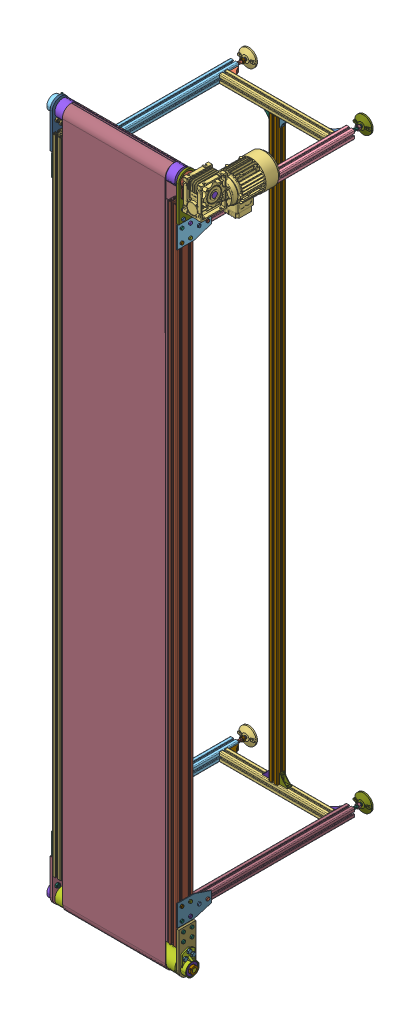
SolidWorks assembly Belt Conveyor.step, configuration Domyślna. Lengths in mm.
Overall size (783.77 3281.47 920.11).
223 component instances, 189 part files, 0 mates.
Components (placement in the parent):
- 8260K11_Mounted Bearing with Three-Bolt Flange.step-1: 8260K11_Mounted Bearing with Three-Bolt Flange.step [Domyślna] at (341.4816 -2455.8636 499.638) x (0 0.005965 0.999982) z (1 0 0) size (100.43 3260.49 665.09)
  - 8260K11_Mounted Bearing with Three-Bolt Flange(Mirror) (3).step-1: 8260K11_Mounted Bearing with Three-Bolt Flange(Mirror) (3).step [Domyślna] at (0 0 -596.825) size (80.98 205.46 51.19)
    - Nut(Mirror) (1).step-1: Nut(Mirror) (1).step [Domyślna] at (0 -65.0875 12.4125) x (-1 0 0) z (0 0 1) size (19.64 19.63 31.4)
    - Nut(Mirror) (1).step-2: Nut(Mirror) (1).step [Domyślna] at (-19 -43.0875 12.4125) x (-1 0 0) z (0 0 1) size (19.64 19.63 31.4)
    - Nut(Mirror) (1).step-3: Nut(Mirror) (1).step [Domyślna] at (19 -43.0875 12.4125) x (-1 0 0) z (0 0 1) size (19.64 19.63 31.4)
    - 4 Hex(Mirror).step-1: 4 Hex(Mirror).step [Domyślna] at (20.8958 -150.1006 3.7625) x (0 0 1) z (-1 0 0) size (21.31 55.25 53.25)
    - 8260K11_Mounted Bearing with Three-Bolt Flange(Mirror) (3)-0.step-1: 8260K11_Mounted Bearing with Three-Bolt Flange(Mirror) (3)-0.step [Domyślna] at origin size (60.74 60.74 12.3)
    - 8260K11_Mounted Bearing with Three-Bolt Flange(Mirror) (3)-1.step-1: 8260K11_Mounted Bearing with Three-Bolt Flange(Mirror) (3)-1.step [Domyślna] at origin size (53.56 53.56 0.76)
    - 8260K11_Mounted Bearing with Three-Bolt Flange(Mirror) (3)-2.step-1: 8260K11_Mounted Bearing with Three-Bolt Flange(Mirror) (3)-2.step [Domyślna] at origin size (50.9 50.9 0.76)
    - 8260K11_Mounted Bearing with Three-Bolt Flange(Mirror) (3)-3.step-1: 8260K11_Mounted Bearing with Three-Bolt Flange(Mirror) (3)-3.step [Domyślna] at origin size (12.3 12.3 12.3)
    - 8260K11_Mounted Bearing with Three-Bolt Flange(Mirror) (3)-4.step-1: 8260K11_Mounted Bearing with Three-Bolt Flange(Mirror) (3)-4.step [Domyślna] at origin size (12.3 12.3 12.3)
    - 8260K11_Mounted Bearing with Three-Bolt Flange(Mirror) (3)-5.step-1: 8260K11_Mounted Bearing with Three-Bolt Flange(Mirror) (3)-5.step [Domyślna] at origin size (12.3 12.3 12.3)
    - 8260K11_Mounted Bearing with Three-Bolt Flange(Mirror) (3)-6.step-1: 8260K11_Mounted Bearing with Three-Bolt Flange(Mirror) (3)-6.step [Domyślna] at origin size (12.3 12.3 12.3)
    - 8260K11_Mounted Bearing with Three-Bolt Flange(Mirror) (3)-7.step-1: 8260K11_Mounted Bearing with Three-Bolt Flange(Mirror) (3)-7.step [Domyślna] at origin size (12.3 12.3 12.3)
    - 8260K11_Mounted Bearing with Three-Bolt Flange(Mirror) (3)-8.step-1: 8260K11_Mounted Bearing with Three-Bolt Flange(Mirror) (3)-8.step [Domyślna] at origin size (12.3 12.3 12.3)
    - 8260K11_Mounted Bearing with Three-Bolt Flange(Mirror) (3)-9.step-1: 8260K11_Mounted Bearing with Three-Bolt Flange(Mirror) (3)-9.step [Domyślna] at origin size (66.58 109.49 25.4)
    - 8260K11_Mounted Bearing with Three-Bolt Flange(Mirror) (3)-10.step-1: 8260K11_Mounted Bearing with Three-Bolt Flange(Mirror) (3)-10.step [Domyślna] at origin size (13.07 13.07 9.52)
    - 8260K11_Mounted Bearing with Three-Bolt Flange(Mirror) (3)-11.step-1: 8260K11_Mounted Bearing with Three-Bolt Flange(Mirror) (3)-11.step [Domyślna] at origin size (33.87 33.87 32.54)
    - 8260K11_Mounted Bearing with Three-Bolt Flange(Mirror) (3)-12.step-1: 8260K11_Mounted Bearing with Three-Bolt Flange(Mirror) (3)-12.step [Domyślna] at origin size (6.25 7.12 6.25)
    - 8260K11_Mounted Bearing with Three-Bolt Flange(Mirror) (3)-13.step-1: 8260K11_Mounted Bearing with Three-Bolt Flange(Mirror) (3)-13.step [Domyślna] at origin size (8.65 8.34 6.25)
    - 8260K11_Mounted Bearing with Three-Bolt Flange(Mirror) (3)-14.step-1: 8260K11_Mounted Bearing with Three-Bolt Flange(Mirror) (3)-14.step [Domyślna] at origin size (80.98 205.46 10)
  - 8260K11_Mounted Bearing with Three-Bolt Flange(Mirror) (4).step-1: 8260K11_Mounted Bearing with Three-Bolt Flange(Mirror) (4).step [Domyślna] at (18.9701 -3180.0156 0) x (0.999929 0.01193 0) z (0 0 -1) size (80.98 205.46 51.19)
    - Nut(Mirror) (2).step-1: Nut(Mirror) (2).step [Domyślna] at (0 -65.0875 12.4125) x (-1 0 0) z (0 0 1) size (19.64 19.63 31.4)
    - Nut(Mirror) (2).step-2: Nut(Mirror) (2).step [Domyślna] at (-19 -43.0875 12.4125) x (-1 0 0) z (0 0 1) size (19.64 19.63 31.4)
    - Nut(Mirror) (2).step-3: Nut(Mirror) (2).step [Domyślna] at (19 -43.0875 12.4125) x (-1 0 0) z (0 0 1) size (19.64 19.63 31.4)
    - 4 Hex(Mirror) (1).step-1: 4 Hex(Mirror) (1).step [Domyślna] at (20.8958 -150.1006 3.7625) x (0 0 1) z (-1 0 0) size (21.31 55.25 53.25)
    - 8260K11_Mounted Bearing with Three-Bolt Flange(Mirror) (4)-15.step-1: 8260K11_Mounted Bearing with Three-Bolt Flange(Mirror) (4)-15.step [Domyślna] at origin size (60.74 60.74 12.3)
    - 8260K11_Mounted Bearing with Three-Bolt Flange(Mirror) (4)-16.step-1: 8260K11_Mounted Bearing with Three-Bolt Flange(Mirror) (4)-16.step [Domyślna] at origin size (53.56 53.56 0.76)
    - 8260K11_Mounted Bearing with Three-Bolt Flange(Mirror) (4)-17.step-1: 8260K11_Mounted Bearing with Three-Bolt Flange(Mirror) (4)-17.step [Domyślna] at origin size (50.9 50.9 0.76)
    - 8260K11_Mounted Bearing with Three-Bolt Flange(Mirror) (4)-18.step-1: 8260K11_Mounted Bearing with Three-Bolt Flange(Mirror) (4)-18.step [Domyślna] at origin size (12.3 12.3 12.3)
    - 8260K11_Mounted Bearing with Three-Bolt Flange(Mirror) (4)-19.step-1: 8260K11_Mounted Bearing with Three-Bolt Flange(Mirror) (4)-19.step [Domyślna] at origin size (12.3 12.3 12.3)
    - 8260K11_Mounted Bearing with Three-Bolt Flange(Mirror) (4)-20.step-1: 8260K11_Mounted Bearing with Three-Bolt Flange(Mirror) (4)-20.step [Domyślna] at origin size (12.3 12.3 12.3)
    - 8260K11_Mounted Bearing with Three-Bolt Flange(Mirror) (4)-21.step-1: 8260K11_Mounted Bearing with Three-Bolt Flange(Mirror) (4)-21.step [Domyślna] at origin size (12.3 12.3 12.3)
    - 8260K11_Mounted Bearing with Three-Bolt Flange(Mirror) (4)-22.step-1: 8260K11_Mounted Bearing with Three-Bolt Flange(Mirror) (4)-22.step [Domyślna] at origin size (12.3 12.3 12.3)
    - 8260K11_Mounted Bearing with Three-Bolt Flange(Mirror) (4)-23.step-1: 8260K11_Mounted Bearing with Three-Bolt Flange(Mirror) (4)-23.step [Domyślna] at origin size (12.3 12.3 12.3)
    - 8260K11_Mounted Bearing with Three-Bolt Flange(Mirror) (4)-24.step-1: 8260K11_Mounted Bearing with Three-Bolt Flange(Mirror) (4)-24.step [Domyślna] at origin size (66.58 109.49 25.4)
    - 8260K11_Mounted Bearing with Three-Bolt Flange(Mirror) (4)-25.step-1: 8260K11_Mounted Bearing with Three-Bolt Flange(Mirror) (4)-25.step [Domyślna] at origin size (13.07 13.07 9.52)
    - 8260K11_Mounted Bearing with Three-Bolt Flange(Mirror) (4)-26.step-1: 8260K11_Mounted Bearing with Three-Bolt Flange(Mirror) (4)-26.step [Domyślna] at origin size (33.87 33.87 32.54)
    - 8260K11_Mounted Bearing with Three-Bolt Flange(Mirror) (4)-27.step-1: 8260K11_Mounted Bearing with Three-Bolt Flange(Mirror) (4)-27.step [Domyślna] at origin size (6.25 7.12 6.25)
    - 8260K11_Mounted Bearing with Three-Bolt Flange(Mirror) (4)-28.step-1: 8260K11_Mounted Bearing with Three-Bolt Flange(Mirror) (4)-28.step [Domyślna] at origin size (8.65 8.34 6.25)
    - 8260K11_Mounted Bearing with Three-Bolt Flange(Mirror) (4)-29.step-1: 8260K11_Mounted Bearing with Three-Bolt Flange(Mirror) (4)-29.step [Domyślna] at origin size (80.98 205.46 10)
  - 8260K11_Mounted Bearing with Three-Bolt Flange(Mirror) (5).step-1: 8260K11_Mounted Bearing with Three-Bolt Flange(Mirror) (5).step [Domyślna] at (0 0 -596.825) size (100.43 3260.49 665.09)
    - 8260K11_Mounted Bearing with Three-Bolt Flange(Mirror) (3)(Mirror) (1).step-1: 8260K11_Mounted Bearing with Three-Bolt Flange(Mirror) (3)(Mirror) (1).step [Domyślna] at (0 0 596.825) size (80.98 205.46 51.19)
      - Nut(Mirror) (1)(Mirror) (1).step-1: Nut(Mirror) (1)(Mirror) (1).step [Domyślna] at (0 -65.0875 -12.4125) x (-1 0 0) z (0 0 1) size (19.64 19.63 31.4)
      - Nut(Mirror) (1)(Mirror) (1).step-2: Nut(Mirror) (1)(Mirror) (1).step [Domyślna] at (-19 -43.0875 -12.4125) x (-1 0 0) z (0 0 1) size (19.64 19.63 31.4)
      - Nut(Mirror) (1)(Mirror) (1).step-3: Nut(Mirror) (1)(Mirror) (1).step [Domyślna] at (19 -43.0875 -12.4125) x (-1 0 0) z (0 0 1) size (19.64 19.63 31.4)
      - 4 Hex(Mirror)(Mirror) (1).step-1: 4 Hex(Mirror)(Mirror) (1).step [Domyślna] at (20.8958 -150.1006 -3.7625) x (0 0 -1) z (1 0 0) size (21.31 55.25 55.26)
      - 8260K11_Mounted Bearing with Three-Bolt Flange(Mirror) (3)(Mirror) (1)-30.step-1: 8260K11_Mounted Bearing with Three-Bolt Flange(Mirror) (3)(Mirror) (1)-30.step [Domyślna] at origin size (60.74 60.74 12.3)
      - 8260K11_Mounted Bearing with Three-Bolt Flange(Mirror) (3)(Mirror) (1)-31.step-1: 8260K11_Mounted Bearing with Three-Bolt Flange(Mirror) (3)(Mirror) (1)-31.step [Domyślna] at origin size (53.56 53.56 0.76)
      - 8260K11_Mounted Bearing with Three-Bolt Flange(Mirror) (3)(Mirror) (1)-32.step-1: 8260K11_Mounted Bearing with Three-Bolt Flange(Mirror) (3)(Mirror) (1)-32.step [Domyślna] at origin size (50.9 50.9 0.76)
      - 8260K11_Mounted Bearing with Three-Bolt Flange(Mirror) (3)(Mirror) (1)-33.step-1: 8260K11_Mounted Bearing with Three-Bolt Flange(Mirror) (3)(Mirror) (1)-33.step [Domyślna] at origin size (12.3 12.3 12.3)
      - 8260K11_Mounted Bearing with Three-Bolt Flange(Mirror) (3)(Mirror) (1)-34.step-1: 8260K11_Mounted Bearing with Three-Bolt Flange(Mirror) (3)(Mirror) (1)-34.step [Domyślna] at origin size (12.3 12.3 12.3)
      - 8260K11_Mounted Bearing with Three-Bolt Flange(Mirror) (3)(Mirror) (1)-35.step-1: 8260K11_Mounted Bearing with Three-Bolt Flange(Mirror) (3)(Mirror) (1)-35.step [Domyślna] at origin size (12.3 12.3 12.3)
      - 8260K11_Mounted Bearing with Three-Bolt Flange(Mirror) (3)(Mirror) (1)-36.step-1: 8260K11_Mounted Bearing with Three-Bolt Flange(Mirror) (3)(Mirror) (1)-36.step [Domyślna] at origin size (12.3 12.3 12.3)
      - 8260K11_Mounted Bearing with Three-Bolt Flange(Mirror) (3)(Mirror) (1)-37.step-1: 8260K11_Mounted Bearing with Three-Bolt Flange(Mirror) (3)(Mirror) (1)-37.step [Domyślna] at origin size (12.3 12.3 12.3)
      - 8260K11_Mounted Bearing with Three-Bolt Flange(Mirror) (3)(Mirror) (1)-38.step-1: 8260K11_Mounted Bearing with Three-Bolt Flange(Mirror) (3)(Mirror) (1)-38.step [Domyślna] at origin size (12.3 12.3 12.3)
      - 8260K11_Mounted Bearing with Three-Bolt Flange(Mirror) (3)(Mirror) (1)-39.step-1: 8260K11_Mounted Bearing with Three-Bolt Flange(Mirror) (3)(Mirror) (1)-39.step [Domyślna] at origin size (66.58 109.49 25.4)
      - 8260K11_Mounted Bearing with Three-Bolt Flange(Mirror) (3)(Mirror) (1)-40.step-1: 8260K11_Mounted Bearing with Three-Bolt Flange(Mirror) (3)(Mirror) (1)-40.step [Domyślna] at origin size (13.07 13.07 9.52)
      - 8260K11_Mounted Bearing with Three-Bolt Flange(Mirror) (3)(Mirror) (1)-41.step-1: 8260K11_Mounted Bearing with Three-Bolt Flange(Mirror) (3)(Mirror) (1)-41.step [Domyślna] at origin size (33.87 33.87 32.54)
      - 8260K11_Mounted Bearing with Three-Bolt Flange(Mirror) (3)(Mirror) (1)-42.step-1: 8260K11_Mounted Bearing with Three-Bolt Flange(Mirror) (3)(Mirror) (1)-42.step [Domyślna] at origin size (6.25 7.12 6.25)
      - 8260K11_Mounted Bearing with Three-Bolt Flange(Mirror) (3)(Mirror) (1)-43.step-1: 8260K11_Mounted Bearing with Three-Bolt Flange(Mirror) (3)(Mirror) (1)-43.step [Domyślna] at origin size (8.65 8.34 6.25)
      - 8260K11_Mounted Bearing with Three-Bolt Flange(Mirror) (3)(Mirror) (1)-44.step-1: 8260K11_Mounted Bearing with Three-Bolt Flange(Mirror) (3)(Mirror) (1)-44.step [Domyślna] at origin size (80.98 205.46 10)
    - 8260K11_Mounted Bearing with Three-Bolt Flange(Mirror) (4)(Mirror).step-1: 8260K11_Mounted Bearing with Three-Bolt Flange(Mirror) (4)(Mirror).step [Domyślna] at (18.9701 -3180.0156 0) x (0.999929 0.01193 0) z (0 0 -1) size (80.98 205.46 51.19)
      - Nut(Mirror) (2)(Mirror).step-1: Nut(Mirror) (2)(Mirror).step [Domyślna] at (0 -65.0875 -12.4125) x (-1 0 0) z (0 0 1) size (19.64 19.63 31.4)
      - Nut(Mirror) (2)(Mirror).step-2: Nut(Mirror) (2)(Mirror).step [Domyślna] at (-19 -43.0875 -12.4125) x (-1 0 0) z (0 0 1) size (19.64 19.63 31.4)
      - Nut(Mirror) (2)(Mirror).step-3: Nut(Mirror) (2)(Mirror).step [Domyślna] at (19 -43.0875 -12.4125) x (-1 0 0) z (0 0 1) size (19.64 19.63 31.4)
      - 4 Hex(Mirror) (1)(Mirror).step-1: 4 Hex(Mirror) (1)(Mirror).step [Domyślna] at (20.8958 -150.1006 -3.7625) x (0 0 -1) z (1 0 0) size (21.31 55.25 55.26)
      - 8260K11_Mounted Bearing with Three-Bolt Flange(Mirror) (4)(Mirror)-45.step-1: 8260K11_Mounted Bearing with Three-Bolt Flange(Mirror) (4)(Mirror)-45.step [Domyślna] at origin size (60.74 60.74 12.3)
      - 8260K11_Mounted Bearing with Three-Bolt Flange(Mirror) (4)(Mirror)-46.step-1: 8260K11_Mounted Bearing with Three-Bolt Flange(Mirror) (4)(Mirror)-46.step [Domyślna] at origin size (53.56 53.56 0.76)
      - 8260K11_Mounted Bearing with Three-Bolt Flange(Mirror) (4)(Mirror)-47.step-1: 8260K11_Mounted Bearing with Three-Bolt Flange(Mirror) (4)(Mirror)-47.step [Domyślna] at origin size (50.9 50.9 0.76)
      - 8260K11_Mounted Bearing with Three-Bolt Flange(Mirror) (4)(Mirror)-48.step-1: 8260K11_Mounted Bearing with Three-Bolt Flange(Mirror) (4)(Mirror)-48.step [Domyślna] at origin size (12.3 12.3 12.3)
      - 8260K11_Mounted Bearing with Three-Bolt Flange(Mirror) (4)(Mirror)-49.step-1: 8260K11_Mounted Bearing with Three-Bolt Flange(Mirror) (4)(Mirror)-49.step [Domyślna] at origin size (12.3 12.3 12.3)
      - 8260K11_Mounted Bearing with Three-Bolt Flange(Mirror) (4)(Mirror)-50.step-1: 8260K11_Mounted Bearing with Three-Bolt Flange(Mirror) (4)(Mirror)-50.step [Domyślna] at origin size (12.3 12.3 12.3)
      - 8260K11_Mounted Bearing with Three-Bolt Flange(Mirror) (4)(Mirror)-51.step-1: 8260K11_Mounted Bearing with Three-Bolt Flange(Mirror) (4)(Mirror)-51.step [Domyślna] at origin size (12.3 12.3 12.3)
      - 8260K11_Mounted Bearing with Three-Bolt Flange(Mirror) (4)(Mirror)-52.step-1: 8260K11_Mounted Bearing with Three-Bolt Flange(Mirror) (4)(Mirror)-52.step [Domyślna] at origin size (12.3 12.3 12.3)
      - 8260K11_Mounted Bearing with Three-Bolt Flange(Mirror) (4)(Mirror)-53.step-1: 8260K11_Mounted Bearing with Three-Bolt Flange(Mirror) (4)(Mirror)-53.step [Domyślna] at origin size (12.3 12.3 12.3)
      - 8260K11_Mounted Bearing with Three-Bolt Flange(Mirror) (4)(Mirror)-54.step-1: 8260K11_Mounted Bearing with Three-Bolt Flange(Mirror) (4)(Mirror)-54.step [Domyślna] at origin size (66.58 109.49 25.4)
      - 8260K11_Mounted Bearing with Three-Bolt Flange(Mirror) (4)(Mirror)-55.step-1: 8260K11_Mounted Bearing with Three-Bolt Flange(Mirror) (4)(Mirror)-55.step [Domyślna] at origin size (13.07 13.07 9.52)
      - 8260K11_Mounted Bearing with Three-Bolt Flange(Mirror) (4)(Mirror)-56.step-1: 8260K11_Mounted Bearing with Three-Bolt Flange(Mirror) (4)(Mirror)-56.step [Domyślna] at origin size (33.87 33.87 32.54)
      - 8260K11_Mounted Bearing with Three-Bolt Flange(Mirror) (4)(Mirror)-57.step-1: 8260K11_Mounted Bearing with Three-Bolt Flange(Mirror) (4)(Mirror)-57.step [Domyślna] at origin size (6.25 7.12 6.25)
      - 8260K11_Mounted Bearing with Three-Bolt Flange(Mirror) (4)(Mirror)-58.step-1: 8260K11_Mounted Bearing with Three-Bolt Flange(Mirror) (4)(Mirror)-58.step [Domyślna] at origin size (8.65 8.34 6.25)
      - 8260K11_Mounted Bearing with Three-Bolt Flange(Mirror) (4)(Mirror)-59.step-1: 8260K11_Mounted Bearing with Three-Bolt Flange(Mirror) (4)(Mirror)-59.step [Domyślna] at origin size (80.98 205.46 10)
    - Nut(Mirror) (3).step-1: Nut(Mirror) (3).step [Domyślna] at (0 -65.0875 12.4125) x (-1 0 0) z (0 0 1) size (19.64 19.63 31.4)
    - Nut(Mirror) (3).step-2: Nut(Mirror) (3).step [Domyślna] at (-19 -43.0875 12.4125) x (-1 0 0) z (0 0 1) size (19.64 19.63 31.4)
    - Nut(Mirror) (3).step-3: Nut(Mirror) (3).step [Domyślna] at (19 -43.0875 12.4125) x (-1 0 0) z (0 0 1) size (19.64 19.63 31.4)
    - 4 Hex(Mirror) (2).step-1: 4 Hex(Mirror) (2).step [Domyślna] at (20.8958 -150.1006 3.7625) x (0 0 1) z (-1 0 0) size (21.31 55.25 53.25)
    - 8260K11_Mounted Bearing with Three-Bolt Flange(Mirror) (5)-60.step-1: 8260K11_Mounted Bearing with Three-Bolt Flange(Mirror) (5)-60.step [Domyślna] at origin size (60.74 60.74 12.3)
    - 8260K11_Mounted Bearing with Three-Bolt Flange(Mirror) (5)-61.step-1: 8260K11_Mounted Bearing with Three-Bolt Flange(Mirror) (5)-61.step [Domyślna] at origin size (53.56 53.56 0.76)
    - 8260K11_Mounted Bearing with Three-Bolt Flange(Mirror) (5)-62.step-1: 8260K11_Mounted Bearing with Three-Bolt Flange(Mirror) (5)-62.step [Domyślna] at origin size (50.9 50.9 0.76)
    - 8260K11_Mounted Bearing with Three-Bolt Flange(Mirror) (5)-63.step-1: 8260K11_Mounted Bearing with Three-Bolt Flange(Mirror) (5)-63.step [Domyślna] at origin size (12.3 12.3 12.3)
    - 8260K11_Mounted Bearing with Three-Bolt Flange(Mirror) (5)-64.step-1: 8260K11_Mounted Bearing with Three-Bolt Flange(Mirror) (5)-64.step [Domyślna] at origin size (12.3 12.3 12.3)
    - 8260K11_Mounted Bearing with Three-Bolt Flange(Mirror) (5)-65.step-1: 8260K11_Mounted Bearing with Three-Bolt Flange(Mirror) (5)-65.step [Domyślna] at origin size (12.3 12.3 12.3)
    - 8260K11_Mounted Bearing with Three-Bolt Flange(Mirror) (5)-66.step-1: 8260K11_Mounted Bearing with Three-Bolt Flange(Mirror) (5)-66.step [Domyślna] at origin size (12.3 12.3 12.3)
    - 8260K11_Mounted Bearing with Three-Bolt Flange(Mirror) (5)-67.step-1: 8260K11_Mounted Bearing with Three-Bolt Flange(Mirror) (5)-67.step [Domyślna] at origin size (12.3 12.3 12.3)
    - 8260K11_Mounted Bearing with Three-Bolt Flange(Mirror) (5)-68.step-1: 8260K11_Mounted Bearing with Three-Bolt Flange(Mirror) (5)-68.step [Domyślna] at origin size (12.3 12.3 12.3)
    - 8260K11_Mounted Bearing with Three-Bolt Flange(Mirror) (5)-69.step-1: 8260K11_Mounted Bearing with Three-Bolt Flange(Mirror) (5)-69.step [Domyślna] at origin size (66.58 109.49 25.4)
    - 8260K11_Mounted Bearing with Three-Bolt Flange(Mirror) (5)-70.step-1: 8260K11_Mounted Bearing with Three-Bolt Flange(Mirror) (5)-70.step [Domyślna] at origin size (13.07 13.07 9.52)
    - 8260K11_Mounted Bearing with Three-Bolt Flange(Mirror) (5)-71.step-1: 8260K11_Mounted Bearing with Three-Bolt Flange(Mirror) (5)-71.step [Domyślna] at origin size (33.87 33.87 32.54)
    - 8260K11_Mounted Bearing with Three-Bolt Flange(Mirror) (5)-72.step-1: 8260K11_Mounted Bearing with Three-Bolt Flange(Mirror) (5)-72.step [Domyślna] at origin size (6.25 7.12 6.25)
    - 8260K11_Mounted Bearing with Three-Bolt Flange(Mirror) (5)-73.step-1: 8260K11_Mounted Bearing with Three-Bolt Flange(Mirror) (5)-73.step [Domyślna] at origin size (8.65 8.34 6.25)
    - 8260K11_Mounted Bearing with Three-Bolt Flange(Mirror) (5)-74.step-1: 8260K11_Mounted Bearing with Three-Bolt Flange(Mirror) (5)-74.step [Domyślna] at origin size (80.98 205.46 10)
  - Nut.step-1: Nut.step [Domyślna] at (0 -65.0875 -12.4125) x (-1 0 0) z (0 0 1) size (19.64 19.63 31.4)
  - Nut.step-2: Nut.step [Domyślna] at (-19 -43.0875 -12.4125) x (-1 0 0) z (0 0 1) size (19.64 19.63 31.4)
  - Nut.step-3: Nut.step [Domyślna] at (19 -43.0875 -12.4125) x (-1 0 0) z (0 0 1) size (19.64 19.63 31.4)
  - 4 Hex.step-1: 4 Hex.step [Domyślna] at (20.8958 -150.1006 -3.7625) x (0 0 -1) z (1 0 0) size (21.31 55.25 55.26)
  - 8260K11_Mounted Bearing with Three-Bolt Flange-75.step-1: 8260K11_Mounted Bearing with Three-Bolt Flange-75.step [Domyślna] at origin size (60.74 60.74 12.3)
  - 8260K11_Mounted Bearing with Three-Bolt Flange-76.step-1: 8260K11_Mounted Bearing with Three-Bolt Flange-76.step [Domyślna] at origin size (53.56 53.56 0.76)
  - 8260K11_Mounted Bearing with Three-Bolt Flange-77.step-1: 8260K11_Mounted Bearing with Three-Bolt Flange-77.step [Domyślna] at origin size (50.9 50.9 0.76)
  - 8260K11_Mounted Bearing with Three-Bolt Flange-78.step-1: 8260K11_Mounted Bearing with Three-Bolt Flange-78.step [Domyślna] at origin size (12.3 12.3 12.3)
  - 8260K11_Mounted Bearing with Three-Bolt Flange-79.step-1: 8260K11_Mounted Bearing with Three-Bolt Flange-79.step [Domyślna] at origin size (12.3 12.3 12.3)
  - 8260K11_Mounted Bearing with Three-Bolt Flange-80.step-1: 8260K11_Mounted Bearing with Three-Bolt Flange-80.step [Domyślna] at origin size (12.3 12.3 12.3)
  - 8260K11_Mounted Bearing with Three-Bolt Flange-81.step-1: 8260K11_Mounted Bearing with Three-Bolt Flange-81.step [Domyślna] at origin size (12.3 12.3 12.3)
  - 8260K11_Mounted Bearing with Three-Bolt Flange-82.step-1: 8260K11_Mounted Bearing with Three-Bolt Flange-82.step [Domyślna] at origin size (12.3 12.3 12.3)
  - 8260K11_Mounted Bearing with Three-Bolt Flange-83.step-1: 8260K11_Mounted Bearing with Three-Bolt Flange-83.step [Domyślna] at origin size (12.3 12.3 12.3)
  - 8260K11_Mounted Bearing with Three-Bolt Flange-84.step-1: 8260K11_Mounted Bearing with Three-Bolt Flange-84.step [Domyślna] at origin size (66.58 109.49 25.4)
  - 8260K11_Mounted Bearing with Three-Bolt Flange-85.step-1: 8260K11_Mounted Bearing with Three-Bolt Flange-85.step [Domyślna] at origin size (13.07 13.07 9.52)
  - 8260K11_Mounted Bearing with Three-Bolt Flange-86.step-1: 8260K11_Mounted Bearing with Three-Bolt Flange-86.step [Domyślna] at origin size (33.87 33.87 32.54)
  - 8260K11_Mounted Bearing with Three-Bolt Flange-87.step-1: 8260K11_Mounted Bearing with Three-Bolt Flange-87.step [Domyślna] at origin size (6.25 7.12 6.25)
  - 8260K11_Mounted Bearing with Three-Bolt Flange-88.step-1: 8260K11_Mounted Bearing with Three-Bolt Flange-88.step [Domyślna] at origin size (8.65 8.34 6.25)
  - 8260K11_Mounted Bearing with Three-Bolt Flange-89.step-1: 8260K11_Mounted Bearing with Three-Bolt Flange-89.step [Domyślna] at origin size (80.98 205.46 10)
- Support 4040.step-1: Support 4040.step [Domyślna] at (115.0482 419.3064 -290) size (620.02 2840.38 899.14)
  - Foot Adjuster v7.step-1: Foot Adjuster v7.step [Domyślna] at (198.0208 74.9024 -27.5496) size (80.02 80 119.51)
    - 91828A420_18-8 Stainless Steel Hex Nut.step-1: 91828A420_18-8 Stainless Steel Hex Nut.step [Domyślna] at (0 9.9637 40.0496) size (19 21.94 10.01)
    - 91828A420_18-8 Stainless Steel Hex Nut.step-2: 91828A420_18-8 Stainless Steel Hex Nut.step [Domyślna] at (0 9.9637 -9.9504) size (19 21.94 10.01)
    - Foot Adjuster v7-90.step-1: Foot Adjuster v7-90.step [Domyślna] at origin size (15 15 12)
    - Foot Adjuster v7-91.step-1: Foot Adjuster v7-91.step [Domyślna] at origin size (11.93 11.93 100.02)
    - Foot Adjuster v7-92.step-1: Foot Adjuster v7-92.step [Domyślna] at origin size (80.02 80 16)
    - Foot Adjuster v7-93.step-1: Foot Adjuster v7-93.step [Domyślna] at origin size (70 70 4)
  - Support 4040(Mirror).step-1: Support 4040(Mirror).step [Domyślna] at (-143.9583 0 0) x (-1 0 0) z (0 0 -1) size (80.02 100 899.14)
    - Foot Adjuster v7(Mirror).step-1: Foot Adjuster v7(Mirror).step [Domyślna] at (198.0208 74.9024 27.5496) size (80.02 80 119.51)
      - 91828A420_18-8 Stainless Steel Hex Nut(Mirror).step-1: 91828A420_18-8 Stainless Steel Hex Nut(Mirror).step [Domyślna] at (0 9.9637 -40.0496) size (19 21.94 10.01)
      - 91828A420_18-8 Stainless Steel Hex Nut(Mirror).step-2: 91828A420_18-8 Stainless Steel Hex Nut(Mirror).step [Domyślna] at (0 9.9637 9.9504) size (19 21.94 10.01)
      - Foot Adjuster v7(Mirror)-94.step-1: Foot Adjuster v7(Mirror)-94.step [Domyślna] at origin size (15 15 12)
      - Foot Adjuster v7(Mirror)-95.step-1: Foot Adjuster v7(Mirror)-95.step [Domyślna] at origin size (11.93 11.93 100.02)
      - Foot Adjuster v7(Mirror)-96.step-1: Foot Adjuster v7(Mirror)-96.step [Domyślna] at origin size (80.02 80 16)
      - Foot Adjuster v7(Mirror)-97.step-1: Foot Adjuster v7(Mirror)-97.step [Domyślna] at origin size (70 70 4)
    - Support 4040(Mirror)-98.step-1: Support 4040(Mirror)-98.step [Domyślna] at origin size (40 40 750)
    - Support 4040(Mirror)-99.step-1: Support 4040(Mirror)-99.step [Domyślna] at origin size (3 100 160.2)
    - Support 4040(Mirror)-100.step-1: Support 4040(Mirror)-100.step [Domyślna] at origin size (15.31 15.06 15.06)
    - Support 4040(Mirror)-101.step-1: Support 4040(Mirror)-101.step [Domyślna] at origin size (15.31 15.06 15.06)
    - Support 4040(Mirror)-102.step-1: Support 4040(Mirror)-102.step [Domyślna] at origin size (15.31 15.06 15.06)
    - Support 4040(Mirror)-103.step-1: Support 4040(Mirror)-103.step [Domyślna] at origin size (15.31 15.06 15.06)
    - Support 4040(Mirror)-104.step-1: Support 4040(Mirror)-104.step [Domyślna] at origin size (15.31 15.06 15.06)
    - Support 4040(Mirror)-105.step-1: Support 4040(Mirror)-105.step [Domyślna] at origin size (15.31 15.06 15.06)
  - Support 4040(Mirror) (1).step-1: Support 4040(Mirror) (1).step [Domyślna] at (0 -2570.2679 0) x (1 0 0) z (0 0 -1) size (620.02 100 899.14)
    - Foot Adjuster v7(Mirror) (1).step-1: Foot Adjuster v7(Mirror) (1).step [Domyślna] at (198.0208 74.9024 27.5496) size (80.02 80 119.51)
      - 91828A420_18-8 Stainless Steel Hex Nut(Mirror) (1).step-1: 91828A420_18-8 Stainless Steel Hex Nut(Mirror) (1).step [Domyślna] at (0 9.9637 -40.0496) size (19 21.94 10.01)
      - 91828A420_18-8 Stainless Steel Hex Nut(Mirror) (1).step-2: 91828A420_18-8 Stainless Steel Hex Nut(Mirror) (1).step [Domyślna] at (0 9.9637 9.9504) size (19 21.94 10.01)
      - Foot Adjuster v7(Mirror) (1)-106.step-1: Foot Adjuster v7(Mirror) (1)-106.step [Domyślna] at origin size (15 15 12)
      - Foot Adjuster v7(Mirror) (1)-107.step-1: Foot Adjuster v7(Mirror) (1)-107.step [Domyślna] at origin size (11.93 11.93 100.02)
      - Foot Adjuster v7(Mirror) (1)-108.step-1: Foot Adjuster v7(Mirror) (1)-108.step [Domyślna] at origin size (80.02 80 16)
      - Foot Adjuster v7(Mirror) (1)-109.step-1: Foot Adjuster v7(Mirror) (1)-109.step [Domyślna] at origin size (70 70 4)
    - Support 4040(Mirror)(Mirror).step-1: Support 4040(Mirror)(Mirror).step [Domyślna] at (-143.9583 0 0) x (-1 0 0) z (0 0 -1) size (80.02 100 899.14)
      - Foot Adjuster v7(Mirror)(Mirror).step-1: Foot Adjuster v7(Mirror)(Mirror).step [Domyślna] at (198.0208 74.9024 -27.5496) size (80.02 80 119.51)
        - 91828A420_18-8 Stainless Steel Hex Nut(Mirror)(Mirror).step-1: 91828A420_18-8 Stainless Steel Hex Nut(Mirror)(Mirror).step [Domyślna] at (0 9.9637 40.0496) size (19 21.94 10.01)
        - 91828A420_18-8 Stainless Steel Hex Nut(Mirror)(Mirror).step-2: 91828A420_18-8 Stainless Steel Hex Nut(Mirror)(Mirror).step [Domyślna] at (0 9.9637 -9.9504) size (19 21.94 10.01)
        - Foot Adjuster v7(Mirror)(Mirror)-110.step-1: Foot Adjuster v7(Mirror)(Mirror)-110.step [Domyślna] at origin size (15 15 12)
        - Foot Adjuster v7(Mirror)(Mirror)-111.step-1: Foot Adjuster v7(Mirror)(Mirror)-111.step [Domyślna] at origin size (11.93 11.93 100.02)
        - Foot Adjuster v7(Mirror)(Mirror)-112.step-1: Foot Adjuster v7(Mirror)(Mirror)-112.step [Domyślna] at origin size (80.02 80 16)
        - Foot Adjuster v7(Mirror)(Mirror)-113.step-1: Foot Adjuster v7(Mirror)(Mirror)-113.step [Domyślna] at origin size (70 70 4)
      - Support 4040(Mirror)(Mirror)-114.step-1: Support 4040(Mirror)(Mirror)-114.step [Domyślna] at origin size (40 40 750)
      - Support 4040(Mirror)(Mirror)-115.step-1: Support 4040(Mirror)(Mirror)-115.step [Domyślna] at origin size (3 100 160.2)
      - Support 4040(Mirror)(Mirror)-116.step-1: Support 4040(Mirror)(Mirror)-116.step [Domyślna] at origin size (15.31 15.02 13.05)
      - Support 4040(Mirror)(Mirror)-117.step-1: Support 4040(Mirror)(Mirror)-117.step [Domyślna] at origin size (15.31 15.02 13.05)
      - Support 4040(Mirror)(Mirror)-118.step-1: Support 4040(Mirror)(Mirror)-118.step [Domyślna] at origin size (15.31 15.02 13.05)
      - Support 4040(Mirror)(Mirror)-119.step-1: Support 4040(Mirror)(Mirror)-119.step [Domyślna] at origin size (15.31 15.02 13.05)
      - Support 4040(Mirror)(Mirror)-120.step-1: Support 4040(Mirror)(Mirror)-120.step [Domyślna] at origin size (15.31 15.02 13.05)
      - Support 4040(Mirror)(Mirror)-121.step-1: Support 4040(Mirror)(Mirror)-121.step [Domyślna] at origin size (15.31 15.02 13.05)
    - Support 4040(Mirror) (1)-122.step-1: Support 4040(Mirror) (1)-122.step [Domyślna] at origin size (40 40 750)
    - Support 4040(Mirror) (1)-123.step-1: Support 4040(Mirror) (1)-123.step [Domyślna] at origin size (3 100 160.2)
    - Support 4040(Mirror) (1)-124.step-1: Support 4040(Mirror) (1)-124.step [Domyślna] at origin size (15.31 15.06 15.06)
    - Support 4040(Mirror) (1)-125.step-1: Support 4040(Mirror) (1)-125.step [Domyślna] at origin size (15.31 15.06 15.06)
    - Support 4040(Mirror) (1)-126.step-1: Support 4040(Mirror) (1)-126.step [Domyślna] at origin size (15.31 15.06 15.06)
    - Support 4040(Mirror) (1)-127.step-1: Support 4040(Mirror) (1)-127.step [Domyślna] at origin size (15.31 15.06 15.06)
    - Support 4040(Mirror) (1)-128.step-1: Support 4040(Mirror) (1)-128.step [Domyślna] at origin size (15.31 15.06 15.06)
    - Support 4040(Mirror) (1)-129.step-1: Support 4040(Mirror) (1)-129.step [Domyślna] at origin size (15.31 15.06 15.06)
  - Component91.step-1: Component91.step [Domyślna] at (-250.2384 -383.8055 -1334.1725) x (-1 0 0) z (0 1 0) size (500 40 2780)
  - Support 4040-130.step-1: Support 4040-130.step [Domyślna] at origin size (40 40 750)
  - Support 4040-131.step-1: Support 4040-131.step [Domyślna] at origin size (3 100 160.2)
  - Support 4040-132.step-1: Support 4040-132.step [Domyślna] at origin size (15.31 15.02 13.05)
  - Support 4040-133.step-1: Support 4040-133.step [Domyślna] at origin size (15.31 15.02 13.05)
  - Support 4040-134.step-1: Support 4040-134.step [Domyślna] at origin size (15.31 15.02 13.05)
  - Support 4040-135.step-1: Support 4040-135.step [Domyślna] at origin size (15.31 15.02 13.05)
  - Support 4040-136.step-1: Support 4040-136.step [Domyślna] at origin size (15.31 15.02 13.05)
  - Support 4040-137.step-1: Support 4040-137.step [Domyślna] at origin size (15.31 15.02 13.05)
- 8260K11_Mounted Bearing with Three-Bolt Flange(Mirror) (3)(Mirror).step-1: 8260K11_Mounted Bearing with Three-Bolt Flange(Mirror) (3)(Mirror).step [Domyślna] at (-255.3434 724.2086 499.638) x (0 -0.005965 0.999982) z (-1 0 0) size (80.98 205.46 51.19)
  - Nut(Mirror) (1)(Mirror).step-1: Nut(Mirror) (1)(Mirror).step [Domyślna] at (0 -65.0875 -12.4125) x (-1 0 0) z (0 0 1) size (19.64 19.63 31.4)
  - Nut(Mirror) (1)(Mirror).step-2: Nut(Mirror) (1)(Mirror).step [Domyślna] at (-19 -43.0875 -12.4125) x (-1 0 0) z (0 0 1) size (19.64 19.63 31.4)
  - Nut(Mirror) (1)(Mirror).step-3: Nut(Mirror) (1)(Mirror).step [Domyślna] at (19 -43.0875 -12.4125) x (-1 0 0) z (0 0 1) size (19.64 19.63 31.4)
  - 4 Hex(Mirror)(Mirror).step-1: 4 Hex(Mirror)(Mirror).step [Domyślna] at (20.8958 -150.1006 -3.7625) x (0 0 -1) z (1 0 0) size (21.31 55.25 55.26)
  - 8260K11_Mounted Bearing with Three-Bolt Flange(Mirror) (3)(Mirror)-138.step-1: 8260K11_Mounted Bearing with Three-Bolt Flange(Mirror) (3)(Mirror)-138.step [Domyślna] at origin size (60.74 60.74 12.3)
  - 8260K11_Mounted Bearing with Three-Bolt Flange(Mirror) (3)(Mirror)-139.step-1: 8260K11_Mounted Bearing with Three-Bolt Flange(Mirror) (3)(Mirror)-139.step [Domyślna] at origin size (53.56 53.56 0.76)
  - 8260K11_Mounted Bearing with Three-Bolt Flange(Mirror) (3)(Mirror)-140.step-1: 8260K11_Mounted Bearing with Three-Bolt Flange(Mirror) (3)(Mirror)-140.step [Domyślna] at origin size (50.9 50.9 0.76)
  - 8260K11_Mounted Bearing with Three-Bolt Flange(Mirror) (3)(Mirror)-141.step-1: 8260K11_Mounted Bearing with Three-Bolt Flange(Mirror) (3)(Mirror)-141.step [Domyślna] at origin size (12.3 12.3 12.3)
  - 8260K11_Mounted Bearing with Three-Bolt Flange(Mirror) (3)(Mirror)-142.step-1: 8260K11_Mounted Bearing with Three-Bolt Flange(Mirror) (3)(Mirror)-142.step [Domyślna] at origin size (12.3 12.3 12.3)
  - 8260K11_Mounted Bearing with Three-Bolt Flange(Mirror) (3)(Mirror)-143.step-1: 8260K11_Mounted Bearing with Three-Bolt Flange(Mirror) (3)(Mirror)-143.step [Domyślna] at origin size (12.3 12.3 12.3)
  - 8260K11_Mounted Bearing with Three-Bolt Flange(Mirror) (3)(Mirror)-144.step-1: 8260K11_Mounted Bearing with Three-Bolt Flange(Mirror) (3)(Mirror)-144.step [Domyślna] at origin size (12.3 12.3 12.3)
  - 8260K11_Mounted Bearing with Three-Bolt Flange(Mirror) (3)(Mirror)-145.step-1: 8260K11_Mounted Bearing with Three-Bolt Flange(Mirror) (3)(Mirror)-145.step [Domyślna] at origin size (12.3 12.3 12.3)
  - 8260K11_Mounted Bearing with Three-Bolt Flange(Mirror) (3)(Mirror)-146.step-1: 8260K11_Mounted Bearing with Three-Bolt Flange(Mirror) (3)(Mirror)-146.step [Domyślna] at origin size (12.3 12.3 12.3)
  - 8260K11_Mounted Bearing with Three-Bolt Flange(Mirror) (3)(Mirror)-147.step-1: 8260K11_Mounted Bearing with Three-Bolt Flange(Mirror) (3)(Mirror)-147.step [Domyślna] at origin size (66.58 109.49 25.4)
  - 8260K11_Mounted Bearing with Three-Bolt Flange(Mirror) (3)(Mirror)-148.step-1: 8260K11_Mounted Bearing with Three-Bolt Flange(Mirror) (3)(Mirror)-148.step [Domyślna] at origin size (13.07 13.07 9.52)
  - 8260K11_Mounted Bearing with Three-Bolt Flange(Mirror) (3)(Mirror)-149.step-1: 8260K11_Mounted Bearing with Three-Bolt Flange(Mirror) (3)(Mirror)-149.step [Domyślna] at origin size (33.87 33.87 32.54)
  - 8260K11_Mounted Bearing with Three-Bolt Flange(Mirror) (3)(Mirror)-150.step-1: 8260K11_Mounted Bearing with Three-Bolt Flange(Mirror) (3)(Mirror)-150.step [Domyślna] at origin size (6.25 7.12 6.25)
  - 8260K11_Mounted Bearing with Three-Bolt Flange(Mirror) (3)(Mirror)-151.step-1: 8260K11_Mounted Bearing with Three-Bolt Flange(Mirror) (3)(Mirror)-151.step [Domyślna] at origin size (8.65 8.34 6.25)
  - 8260K11_Mounted Bearing with Three-Bolt Flange(Mirror) (3)(Mirror)-152.step-1: 8260K11_Mounted Bearing with Three-Bolt Flange(Mirror) (3)(Mirror)-152.step [Domyślna] at origin size (80.98 205.46 10)
- Frame8080.step-1: Frame8080.step [Domyślna] at (178.8966 634.1725 813.0691) x (0 0 -1) z (0 -1 0) size (80 40 3000)
- 8080 v1(Mirror).step-1: 8080 v1(Mirror).step [Domyślna] at (-92.7585 634.1725 813.0691) x (0 0 -1) z (0 1 0) size (80 40 3000)
- Belt doang v4.step-1: Belt doang v4.step [Domyślna] at (240 0 0) size (480 3259.3 84.09)
- Angle Bracket v1.step-1: Angle Bracket v1.step [Domyślna] at (54.0691 484.1725 -220) x (0 0 1) z (1 0 0) size (20 45.8 38.8)
- Angle Bracket v1(Mirror) (1).step-1: Angle Bracket v1(Mirror) (1).step [Domyślna] at (32.0691 484.1725 -220) x (0 0 1) z (1 0 0) size (20 45.8 38.8)
- Angle Bracket v1(Mirror) (2).step-1: Angle Bracket v1(Mirror) (2).step [Domyślna] at (54.0691 -2215.8275 -220) x (0 0 1) z (-1 0 0) size (20 45.8 38.8)
- Angle Bracket v1(Mirror) (1)(Mirror).step-1: Angle Bracket v1(Mirror) (1)(Mirror).step [Domyślna] at (32.0691 -2215.8275 -220) x (0 0 1) z (-1 0 0) size (20 45.8 38.8)
- Angle Bracket v1(Mirror) (1)(Mirror).step-2: Angle Bracket v1(Mirror) (1)(Mirror).step [Domyślna] at (302.0691 -2235.0775 -240) x (0 1 0) z (-1 0 0) size (20 45.8 38.8)
- Angle Bracket v1(Mirror) (1)(Mirror)(Mirror).step-1: Angle Bracket v1(Mirror) (1)(Mirror)(Mirror).step [Domyślna] at (-215.9309 -2235.0775 -240) x (0 1 0) z (-1 0 0) size (20 45.8 38.8)
- Angle Bracket v1(Mirror) (1)(Mirror)(Mirror) (1).step-1: Angle Bracket v1(Mirror) (1)(Mirror)(Mirror) (1).step [Domyślna] at (302.0691 503.4225 -240) x (0 -1 0) z (1 0 0) size (20 45.8 38.8)
- Angle Bracket v1(Mirror) (1)(Mirror)(Mirror)(Mirror).step-1: Angle Bracket v1(Mirror) (1)(Mirror)(Mirror)(Mirror).step [Domyślna] at (-215.9309 503.4225 -240) x (0 -1 0) z (1 0 0) size (20 45.8 38.8)
- Motor.step-1: Motor.step [Domyślna] at (907.3504 750.0663 528.9842) x (-1 0 0) z (0 0.005965 0.999982) size (139.37 222.5 348.5)
- Belt Conv Alu - BU.step-1: Belt Conv Alu - BU.step [Domyślna] at origin size (500 3000 30)
- Belt Conv Alu - BU-153.step-1: Belt Conv Alu - BU-153.step [Domyślna] at origin size (10 1 1)
- Belt Conv Alu - BU-154.step-1: Belt Conv Alu - BU-154.step [Domyślna] at origin size (10 1 1)
- Belt Conv Alu - BU-155.step-1: Belt Conv Alu - BU-155.step [Domyślna] at origin size (665 76 76)
- Belt Conv Alu - BU-156.step-1: Belt Conv Alu - BU-156.step [Domyślna] at origin size (760 76 76)
- Belt Conv Alu - BU-157.step-1: Belt Conv Alu - BU-157.step [Domyślna] at origin size (40 2700 40)
